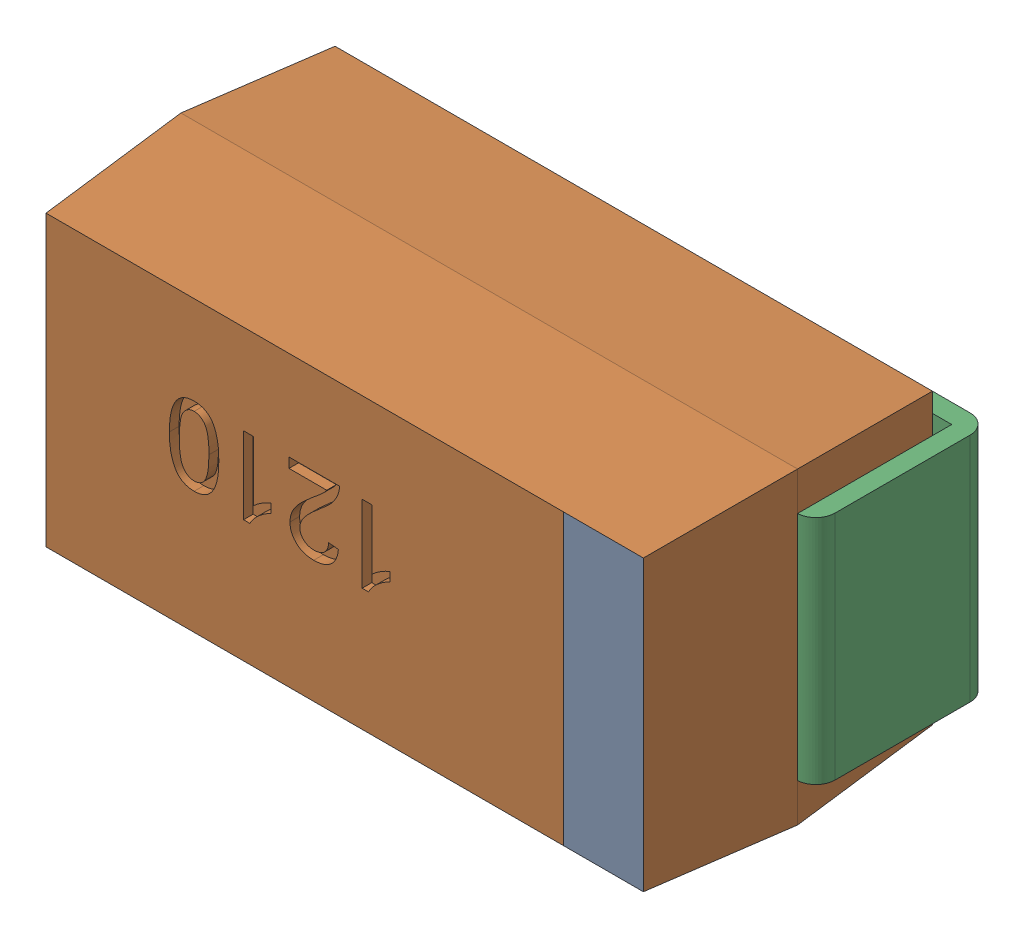
SolidWorks assembly C16, configuration Default. Lengths in mm.
Overall size (3.39 1.6 1.65).
4 component instances, 2 part files, 0 mates.
Components (placement in the parent):
- User_Library-Tantalum_Capacitor_Case_A-1: User_Library-Tantalum_Capacitor_Case_A [Default] at (50.2709 27.4999 0.05) x (-1 0 0) z (0 0 1) size (3.39 1.6 1.65)
  - User_Library-Tantalum_Capacitor_Case_A_Tantalum_case_A_part1-1: User_Library-Tantalum_Capacitor_Case_A_Tantalum_case_A_part1 [Default] at (-1.5973 -0.8 0.1) size (3.2 1.6 1.6)
  - User_Library-Tantalum_Capacitor_Case_A_Tantalum_case_A_part2-1: User_Library-Tantalum_Capacitor_Case_A_Tantalum_case_A_part2 [Default] at (-0.8925 -0.6 0.05) x (-1 0 0) z (0 0 -1) size (0.8 1.2 0.9)
  - User_Library-Tantalum_Capacitor_Case_A_Tantalum_case_A_part2-2: User_Library-Tantalum_Capacitor_Case_A_Tantalum_case_A_part2 [Default] at (0.8979 0.6 0.05) x (1 0 0) z (0 0 -1) size (0.8 1.2 0.9)
